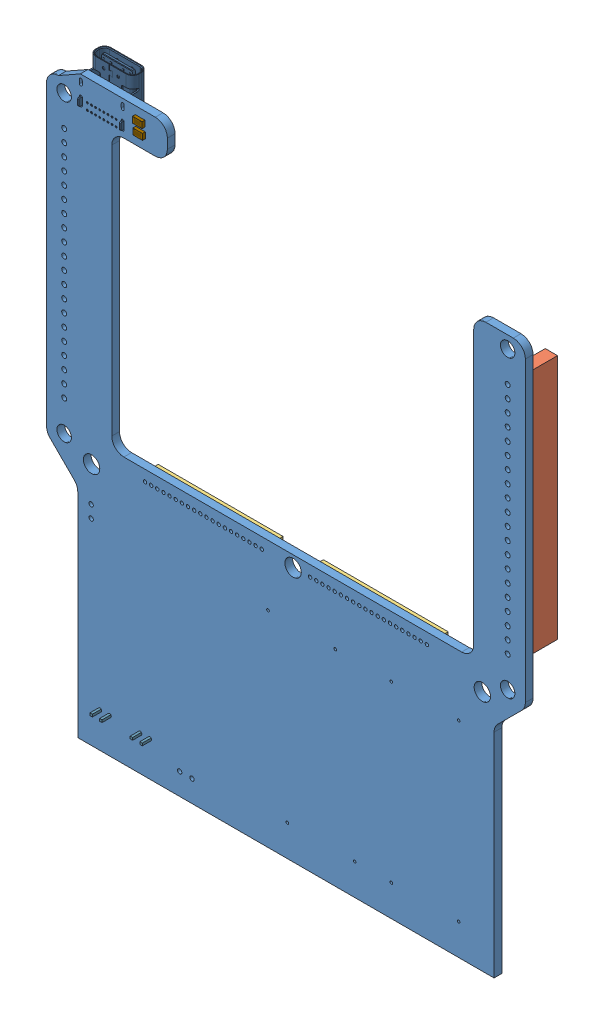
SolidWorks assembly Mainboard_Calculator, configuration Default. Lengths in mm.
Overall size (99 121.92 10.87).
34 component instances, 18 part files, 0 mates.
Components (placement in the parent):
- Mainboard_Calculator_BOARD-1: Mainboard_Calculator_BOARD [Default] at origin size (99 119.09 1.59)
- SAMTEC_SSM-120-L-SV-BE_SSM-120-L-SV-BE-1-1: SAMTEC_SSM-120-L-SV-BE_SSM-120-L-SV-BE-1 [Default] at (122.4793 119.9392 0.0025) x (0 -1 0) z (0 0 -1) size (50.8 4.57 7.49)
- SAMTEC_SSM-120-L-SV-BE_SSM-120-L-SV-BE-1-2: SAMTEC_SSM-120-L-SV-BE_SSM-120-L-SV-BE-1 [Default] at (30.8107 119.9392 0.0025) x (0 -1 0) z (0 0 -1) size (50.8 4.57 7.49)
- M50-3132045_20pos_passthru_header_0.05__pitch-1-1: M50-3132045_20pos_passthru_header_0.05__pitch-1 [Default] at (47.515 89.1692 0.0025) x (1 0 0) z (0 0 -1) size (25.8 3.1 2.1)
- M50-3132045_20pos_passthru_header_0.05__pitch-1-2: M50-3132045_20pos_passthru_header_0.05__pitch-1 [Default] at (81.645 89.1692 0.0025) x (1 0 0) z (0 0 -1) size (25.8 3.1 2.1)
- SOT-23-6_RIT_RT9526AGE-1-1: SOT-23-6_RIT_RT9526AGE-1 [Default] at (54.7972 50.258 0.0025) x (-1 0 0) z (0 0 -1) size (3 3.11 1.31)
- RES_0805_2012_RC0805FR-1315KL-1-1: RES_0805_2012_RC0805FR-1315KL-1 [Default] at (49.8709 48.4515 0.0025) x (0 -1 0) z (0 0 -1) size (2 1.25 0.6)
- RES_0805_2012_RC0805FR-07110KL-1-1: RES_0805_2012_RC0805FR-07110KL-1 [Default] at (50.1289 53.9354 0.0025) x (0 1 0) z (0 0 -1) size (2 1.25 0.6)
- CAP_0603_1608_C1608X7R1C105K080AC-1-1: CAP_0603_1608_C1608X7R1C105K080AC-1 [Default] at (52.8386 46.8386 0.0025) x (1 0 0) z (0 0 -1) size (1.6 0.82 0.82)
- CAP_0603_1608_C1608X7R1C105K080AC-1-2: CAP_0603_1608_C1608X7R1C105K080AC-1 [Default] at (57.8063 49.8709 0.0025) x (0 -1 0) z (0 0 -1) size (1.6 0.82 0.82)
- CAP_0603_1608_GRM188R61E106KA73J-1-1: CAP_0603_1608_GRM188R61E106KA73J-1 [Default] at (59.3547 49.8709 0.0025) x (0 -1 0) z (0 0 -1) size (1.6 0.82 0.82)
- CAP_0603_1608_GRM188R61E106KA73J-1-2: CAP_0603_1608_GRM188R61E106KA73J-1 [Default] at (58.4676 60.9676 0.0025) x (-1 0 0) z (0 0 -1) size (1.6 0.82 0.82)
- CAP_0603_1608_GRM188R61E106KA73J-1-3: CAP_0603_1608_GRM188R61E106KA73J-1 [Default] at (58.4676 59.4838 0.0025) x (-1 0 0) z (0 0 -1) size (1.6 0.82 0.82)
- RES_0805_2012_RC0805JR-075K1L-1-1: RES_0805_2012_RC0805JR-075K1L-1 [Default] at (46.516 153.29 1.5887) size (2 1.25 0.6)
- RES_0805_2012_RC0805JR-075K1L-1-2: RES_0805_2012_RC0805JR-075K1L-1 [Default] at (46.5805 151.2255 1.5887) size (2 1.25 0.6)
- FP-USB4085-GF-A-MFG_CMP-196119-000001-2-1: FP-USB4085-GF-A-MFG_CMP-196119-000001-2 [Default] at (38.5806 153.7416 0.0025) x (1 0 0) z (0 0 -1) size (9.03 9.17 5.57)
- KSTN-5019_V_CMP-1672-00008-1-2: KSTN-5019_V_CMP-1672-00008-1 [Default] at (59.6289 70.8386 0.0025) x (0 1 0) z (0 0 -1) size (3.81 2.03 2.29)
- KSTN-5019_V_CMP-1672-00008-1-3: KSTN-5019_V_CMP-1672-00008-1 [Default] at (54.9838 60.2579 0.0025) x (-1 0 0) z (0 0 -1) size (3.81 2.03 2.29)
- KSTN-5019_V_CMP-1672-00008-1-4: KSTN-5019_V_CMP-1672-00008-1 [Default] at (61.5644 56.3225 0.0025) x (0 1 0) z (0 0 -1) size (3.81 2.03 2.29)
- RES_0603_1608_RC0603FR-0724K3L-1-1: RES_0603_1608_RC0603FR-0724K3L-1 [Default] at (60.5967 63.8708 0.0025) x (0 1 0) z (0 0 -1) size (1.6 0.8 0.45)
- RES_0603_1608_RC0603FR-07220KL-1-1: RES_0603_1608_RC0603FR-07220KL-1 [Default] at (59.7579 66.0644 0.0025) x (-1 0 0) z (0 0 -1) size (1.6 0.8 0.45)
- JST-S2B-PH-K-S_V_CMP-1755-00004-1-1: JST-S2B-PH-K-S_V_CMP-1755-00004-1 [Default] at (47.516 41.2273 0.0025) x (-1 0 0) z (0 0 -1) size (5.9 7.6 8.2)
- JST-S2B-PH-K-S_V_CMP-1755-00004-1-2: JST-S2B-PH-K-S_V_CMP-1755-00004-1 [Default] at (39.1935 41.2273 0.0025) x (-1 0 0) z (0 0 -1) size (5.9 7.6 8.2)
- FP-XGL4030-MFG_CMP-11268-000073-1-1: FP-XGL4030-MFG_CMP-11268-000073-1 [Default] at (57.9515 56.3225 0.0025) x (1 0 0) z (0 0 -1) size (4 4 3.1)
- ALCHITRYMALE_Alchitry_Male-1-1: ALCHITRYMALE_Alchitry_Male-1 [Default] at (105.3917 41.6155 0.0025) x (1 0 0) z (0 0 -1) size (15.2 5.4 5)
- ALCHITRYMALE_Alchitry_Male-1-2: ALCHITRYMALE_Alchitry_Male-1 [Default] at (83.8917 41.6155 0.0025) x (1 0 0) z (0 0 -1) size (15.2 5.4 5)
- ALCHITRYMALE_Alchitry_Male-1-3: ALCHITRYMALE_Alchitry_Male-1 [Default] at (105.3917 77.6155 0.0025) x (1 0 0) z (0 0 -1) size (15.2 5.4 5)
- ALCHITRYMALE_Alchitry_Male-1-4: ALCHITRYMALE_Alchitry_Male-1 [Default] at (79.8917 77.6155 0.0025) x (1 0 0) z (0 0 -1) size (15.2 5.4 5)
- CAPC1608X100X20ML10_CMP-2000-05441-1-1: CAPC1608X100X20ML10_CMP-2000-05441-1 [Default] at (56.7902 69.4192 0.0025) x (1 0 0) z (0 0 -1) size (1.7 0.9 1)
- CAPC1608X100X20ML10_CMP-2000-05441-1-2: CAPC1608X100X20ML10_CMP-2000-05441-1 [Default] at (56.7902 67.7418 0.0025) x (1 0 0) z (0 0 -1) size (1.7 0.9 1)
- CAPC1608X100X20ML10_CMP-2000-05441-1-3: CAPC1608X100X20ML10_CMP-2000-05441-1 [Default] at (56.7902 71.0966 0.0025) x (1 0 0) z (0 0 -1) size (1.7 0.9 1)
- CAPC1608X100X20ML10_CMP-2000-05441-1-4: CAPC1608X100X20ML10_CMP-2000-05441-1 [Default] at (56.7902 66.0644 0.0025) x (1 0 0) z (0 0 -1) size (1.7 0.9 1)
- CAPC1608X100X20ML10_CMP-2000-05441-1-5: CAPC1608X100X20ML10_CMP-2000-05441-1 [Default] at (59.7579 67.7418 0.0025) x (-1 0 0) z (0 0 -1) size (1.7 0.9 1)
- SOT95P280X145-6N_TLV61070ADBVR-1-1: SOT95P280X145-6N_TLV61070ADBVR-1 [Default] at (57.7378 63.466 0.0025) x (1 0 0) z (0 0 -1) size (3 3.05 1.45)
